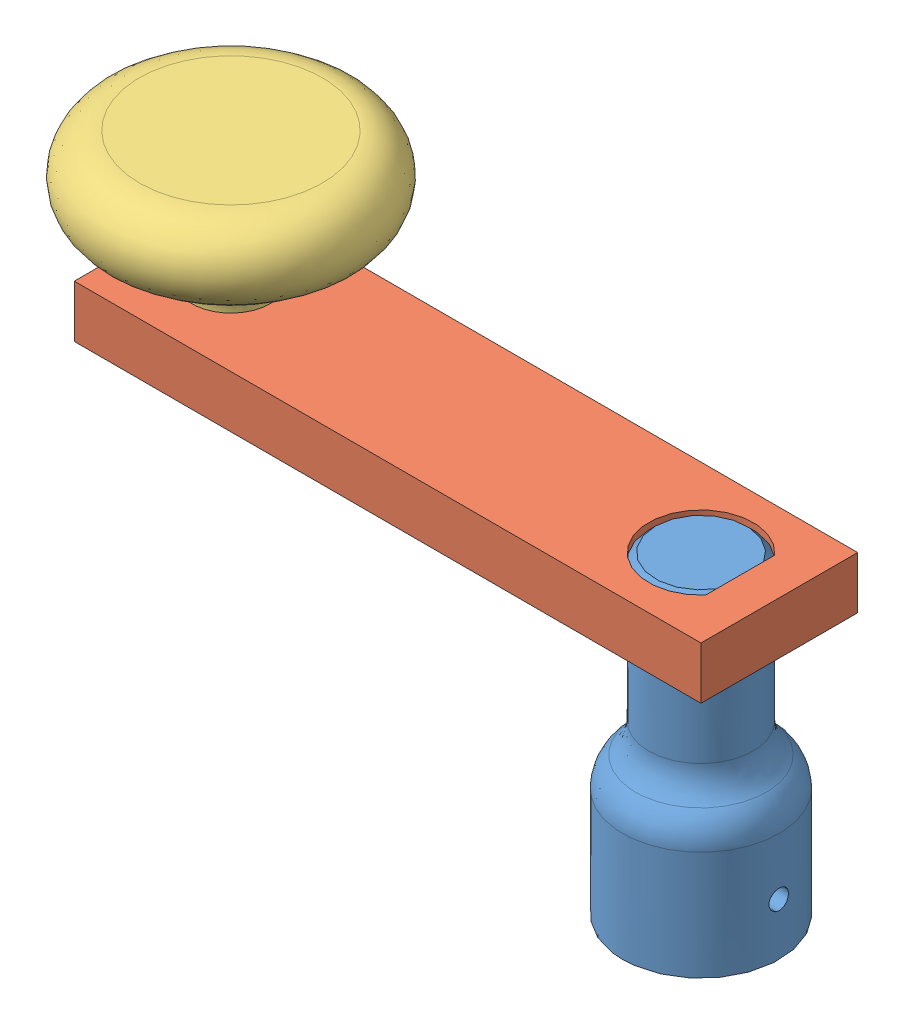
SolidWorks assembly crank-assy_&, configuration Default. Lengths in mm.
Overall size (89.08 53.98 44.81).
3 component instances, 3 part files, 8 mates.
Components (placement in the parent):
- crank-shaft_&-1: crank-shaft_& [Default] at origin size (19.05 38.1 19.05)
- crank-arm_&-1: crank-arm_& [Default] at (-66.675 31.75 -9.525) size (76.2 6.35 19.05)
- crank-knob_&-1: crank-knob_& [Default] at (-57.15 31.75 0) x (0.661436 0 -0.750001) z (0.750001 0 0.661436) size (31.75 22.23 31.75)
Mates (geometry in assembly coordinates):
- Coincident1: coincident aligned: plane of crank-shaft_&-1 through (0 0 0) normal (0 0 1); plane of assembly through (0 0 0) normal (0 0 1)
- Coincident2: coincident aligned: plane of crank-shaft_&-1 through (0 0 0) normal (0 1 0); plane of assembly through (0 0 0) normal (0 1 0)
- Coincident3: coincident aligned: plane of crank-shaft_&-1 through (0 0 0) normal (1 0 0); plane of assembly through (0 0 0) normal (1 0 0)
- Concentric1: concentric anti-aligned: cylinder of crank-shaft_&-1 through (0 38.1 0) axis (0 -1 0) radius 6.35; cylinder of crank-arm_&-1 through (0 31.75 0) axis (0 1 0) radius 6.35
- Parallel1: parallel anti-aligned: plane of crank-shaft_&-1 through (4.7625 31.75 4.2001) normal (1 0 0); plane of crank-arm_&-1 through (4.7625 31.75 -4.2001) normal (-1 0 0)
- Coincident4: coincident anti-aligned: plane of crank-shaft_&-1 through (0 31.75 0) normal (0 1 0); plane of crank-arm_&-1 through (-66.675 31.75 9.525) normal (0 -1 0)
- Concentric2: concentric anti-aligned: cylinder of crank-arm_&-1 through (-57.15 31.75 0) axis (0 1 0) radius 2.3813; cylinder of crank-knob_&-1 through (-57.15 31.75 0) axis (0 -1 0) radius 2.3813
- Coincident5: coincident anti-aligned: plane of crank-arm_&-1 through (9.525 38.1 9.525) normal (0 1 0); plane of crank-knob_&-1 through (-53.9999 38.1 -3.5719) normal (0 -1 0)
